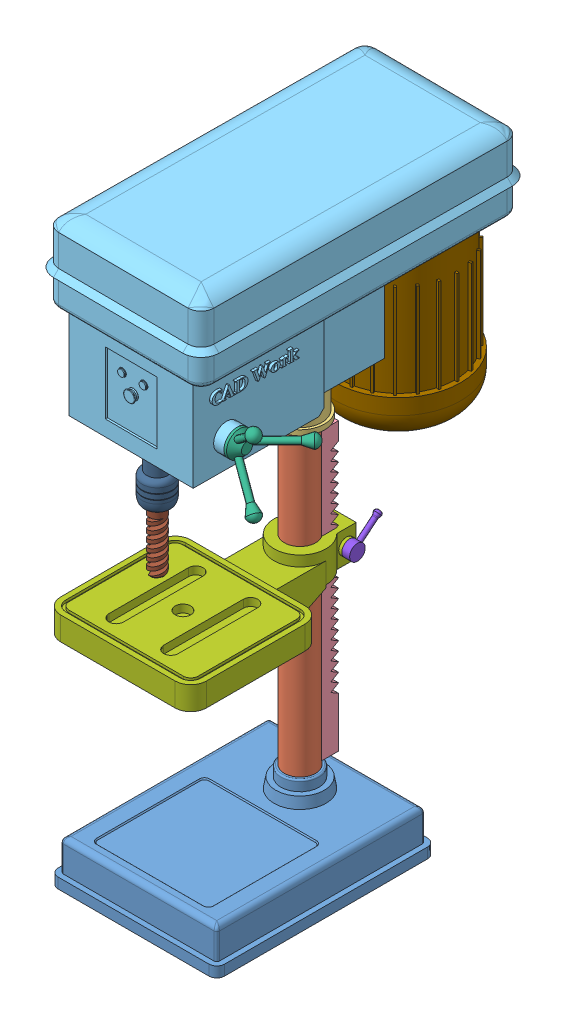
SolidWorks assembly Drill machine, configuration Default. Lengths in mm.
Overall size (383.7 1128 679.66).
11 component instances, 11 part files, 19 mates.
Components (placement in the parent):
- 3-1: 3 [Default] at (164.5831 129.7413 338.2651) size (320 120 420)
- Part1-1: Part1 [Default] at (164.5831 229.7413 228.2651) size (60 600 60)
- Part4-1: Part4 [Default] at (164.5831 829.7413 228.2651) x (0.999974 0 0.00723) z (-0.00723 0 0.999974) size (94 120 94)
- Part2-4: Part2 [Default] at (164.5831 259.7413 248.2651) x (0 0 -1) z (1 0 0) size (32.42 550 50)
- Part3-1: Part3 [Default] at (163.7107 929.7413 360.7622) x (0.999978 0 0.006584) z (-0.006584 0 0.999978) size (320 342 630)
- Part5-1: Part5 [Default] at (327.8775 984.7413 487.8459) x (-0.00569 -0.503317 0.864083) z (-0.999978 0 -0.006584) size (156.63 139.03 102.51)
- Part6-1: Part6 [Default] at (164.5831 573.4475 228.2651) size (280 115 423)
- Part7-1: Part7 [Default] at (205.5831 603.4475 173.9115) x (0 0.637497 -0.770453) z (-1 0 0) size (80 30 20)
- motor-1: motor [Default] at (165.8176 771.7413 40.7692) x (0 0 -1) z (0 1 0) size (240 240 428)
- Part8-1: Part8 [Default] at (162.7889 875.7413 500.7592) x (0.995185 0 -0.09801) z (0.09801 0 0.995185) size (59.29 165.09 59.29)
- drill1-1: drill1 [Default] at (162.7889 705.7413 500.7592) size (32.15 138.93 35.26)
Mates (geometry in assembly coordinates):
- Coincident1: coincident anti-aligned: plane of 3-1 through (164.5831 229.7413 228.2651) normal (0 1 0); plane of Part1-1 through (164.5831 229.7413 228.2651) normal (0 -1 0)
- Concentric1: concentric anti-aligned: cylinder of 3-1 through (164.5831 229.7413 228.2651) axis (0 1 0) radius 30.015; cylinder of Part1-1 through (164.5831 829.7413 228.2651) axis (0 -1 0) radius 30
- Concentric2: concentric aligned: line of Part1-1 through (164.5831 829.7413 228.2651) axis (0 -1 0); cylinder of Part4-1 through (164.5831 839.7413 228.2651) axis (0 -1 0) radius 47
- Distance4: distance = 20 mm anti-aligned: plane of Part2-4 through (164.5831 809.7413 248.2651) normal (0 1 0); plane of Part4-1 through (164.5831 829.7413 228.2651) normal (0 -1 0)
- Coincident5: coincident anti-aligned: plane of Part4-1 through (164.5831 949.7413 228.2651) normal (0 1 0); plane of Part3-1 through (-13.9563 949.7413 309.5913) normal (0 -1 0)
- Concentric8: concentric aligned: cylinder of Part4-1 through (164.5831 949.7413 228.2651) axis (0 -1 0) radius 42; cylinder of Part3-1 through (164.5831 1068.5918 228.2651) axis (0 -1 0) radius 42.02
- Coincident6: coincident anti-aligned: plane of Part3-1 through (282.8784 984.7413 487.5496) normal (0.999978 0 0.006584); plane of Part5-1 through (282.8784 984.7413 487.5496) normal (-0.999978 0 -0.006584)
- Concentric9: concentric anti-aligned: cylinder of Part3-1 through (282.8784 984.7413 487.5496) axis (0.999978 0 0.006584) radius 20; cylinder of Part5-1 through (302.878 984.7413 487.6813) axis (-0.999978 0 -0.006584) radius 19.985
- Concentric10: concentric anti-aligned: cylinder of Part1-1 through (164.5831 829.7413 228.2651) axis (0 -1 0) radius 30; cylinder of Part2-4 through (164.5831 231.3686 228.2651) axis (0 1 0) radius 30
- Concentric11: concentric anti-aligned: cylinder of Part1-1 through (164.5831 829.7413 228.2651) axis (0 -1 0) radius 30; cylinder of Part6-1 through (164.5831 547.4475 228.2651) axis (0 1 0) radius 30.015
- Parallel1: parallel anti-aligned: plane of Part2-4 through (189.5831 809.7413 204.9638) normal (1 0 0); plane of Part6-1 through (189.5981 547.4475 211.6775) normal (-1 0 0)
- Concentric12: concentric aligned: cylinder of Part6-1 through (199.5831 603.4475 173.9115) axis (1 0 0) radius 12.5; cylinder of Part7-1 through (185.5831 603.4475 173.9115) axis (1 0 0) radius 12.485
- Coincident8: coincident anti-aligned: plane of Part6-1 through (205.5831 603.4475 173.9115) normal (1 0 0); plane of Part7-1 through (205.5831 603.4475 173.9115) normal (-1 0 0)
- Concentric13: concentric aligned: cylinder of Part3-1 through (165.8176 1209.7413 40.7692) axis (0 -1 0) radius 12.5; cylinder of motor-1 through (165.8176 1199.7413 40.7692) axis (0 -1 0) radius 12.5
- Coincident9: coincident anti-aligned: plane of Part3-1 through (41.2154 1109.7413 -20.0526) normal (0 -1 0); plane of motor-1 through (165.8176 1109.7413 40.7692) normal (0 1 0)
- Concentric14: concentric aligned: cylinder of Part3-1 through (162.7889 985.7413 500.7592) axis (0 -1 0) radius 20; cylinder of Part8-1 through (162.7889 985.7413 500.7592) axis (0 -1 0) radius 19.985
- Coincident10: coincident anti-aligned: plane of Part3-1 through (162.7889 985.7413 500.7592) normal (0 -1 0); plane of Part8-1 through (162.7889 985.7413 500.7592) normal (0 1 0)
- Concentric15: concentric aligned: cylinder of Part8-1 through (162.7889 855.7413 500.7592) axis (0 -1 0) radius 15; line of drill1-1 through (162.7889 835.7413 500.7592) axis (0 -1 0)
- Distance5: distance = 20 mm anti-aligned: plane of drill1-1 through (162.7889 835.7413 500.7592) normal (0 1 0); plane of Part8-1 through (162.7889 855.7413 500.7592) normal (0 -1 0)
